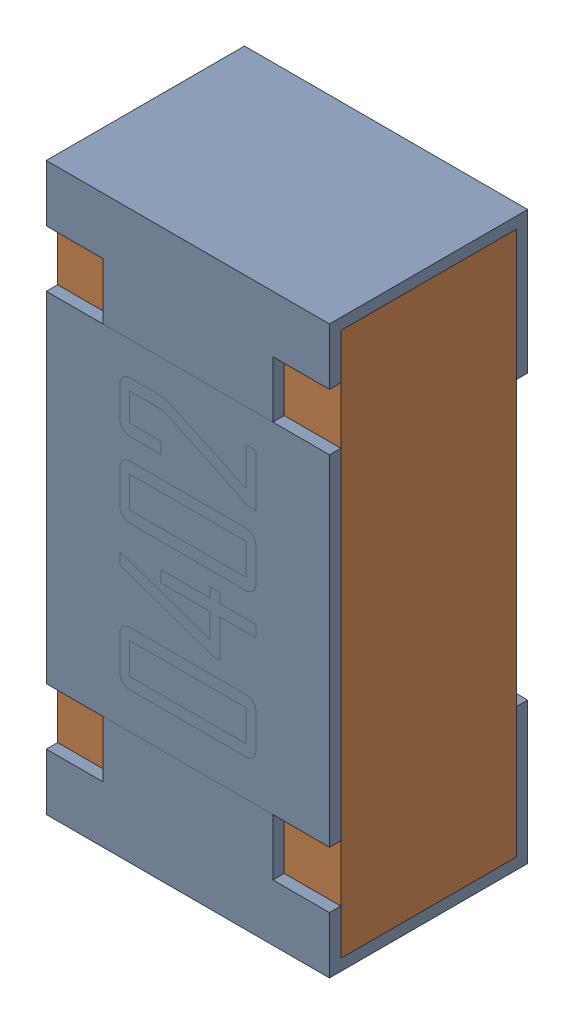
SolidWorks assembly R7, configuration Default. Lengths in mm.
Overall size (0.5 1 0.35).
3 component instances, 2 part files, 0 mates.
Components (placement in the parent):
- R7-subassembly-1-1: R7-subassembly-1 [Default] at (-8.5 7.7499 0) x (0 1 0) z (1 0 0) size (1 0.35 0.5)
  - 0402 resistor-1: 0402 resistor [Default] at origin size (1 0.35 0.5)
  - 0402 resistor-1-1: 0402 resistor-1 [Default] at origin size (0.96 0.31 0.5)
